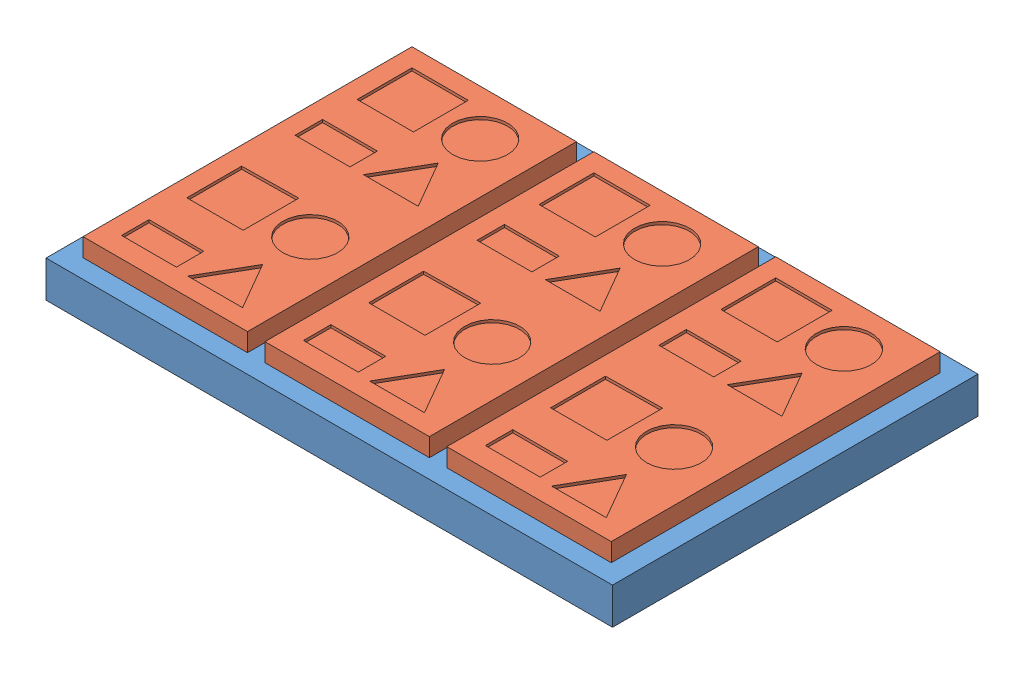
SolidWorks assembly Assem3, configuration Default. Lengths in mm.
Overall size (620 60 400).
4 component instances, 2 part files, 6 mates.
Components (placement in the parent):
- Part22-1: Part22 [Default] at (246.4151 546.7442 744.344) size (620 40 400)
- Part4-11: Part4 [Default] at (46.3952 566.7442 743.8173) size (180 20 360)
- Part4-12: Part4 [Default] at (245.4646 566.7442 743.8173) size (180 20 360)
- Part4-13: Part4 [Default] at (444.5162 566.7442 743.8173) size (180 20 360)
Mates (geometry in assembly coordinates):
- Coincident48: coincident anti-aligned: plane of Part22-1 through (246.4151 546.7442 744.344) normal (0 1 0); plane of Part4-11 through (46.3952 546.7442 743.8173) normal (0 -1 0)
- Coincident53: coincident anti-aligned: plane of Part22-1 through (246.4151 546.7442 744.344) normal (0 1 0); plane of Part4-12 through (245.4646 546.7442 743.8173) normal (0 -1 0)
- Coincident54: coincident anti-aligned: plane of Part22-1 through (246.4151 546.7442 744.344) normal (0 1 0); plane of Part4-13 through (444.5162 546.7442 743.8173) normal (0 -1 0)
- Distance49: distance = 380 mm: line of Part4-11 through (-43.6048 566.7442 923.8173) axis (1 0 0); line of Part22-1 through (556.4151 546.7442 544.344) axis (-1 0 0)
- Distance51: distance = 380 mm: line of Part4-12 through (155.4646 566.7442 923.8173) axis (1 0 0); line of Part22-1 through (556.4151 546.7442 544.344) axis (-1 0 0)
- Distance52: distance = 380 mm: line of Part4-13 through (354.5162 566.7442 923.8173) axis (1 0 0); line of Part22-1 through (556.4151 546.7442 544.344) axis (-1 0 0)
